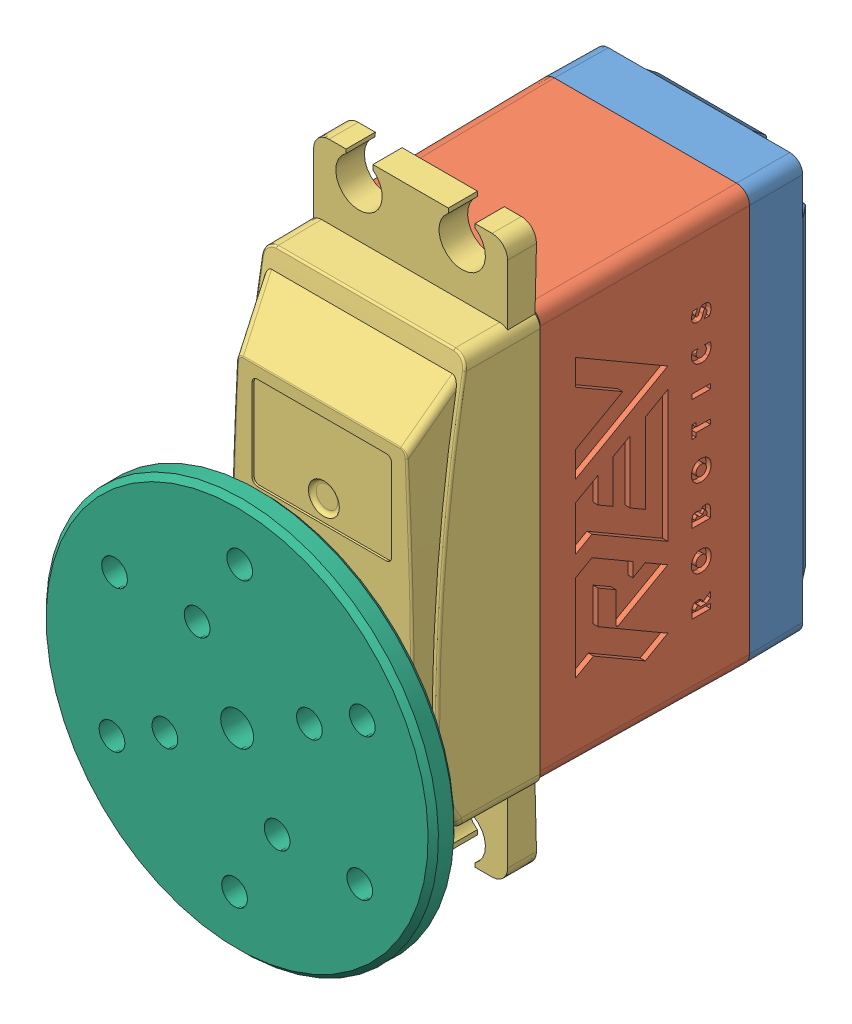
SolidWorks assembly ServoSmartRobotHorn, configuration Default. Lengths in mm.
Overall size (52.15 63.13 46.05).
7 component instances, 6 part files, 2 mates.
Components (placement in the parent):
- PART_ASSEM_ServoSmartRobot-1: PART_ASSEM_ServoSmartRobot [Default] at (95.7961 57.5954 124.6222) size (20.24 54 43.55) (flexible)
  - PART_ServoSmartRobot_A-1: PART_ServoSmartRobot_A [Default] at (-14.7745 1.1024 -40.9494) x (-1 0 0) z (0 0 -1) size (20.15 40.13 8.5)
  - PART_ServoSmartRobot_E-1: PART_ServoSmartRobot_E [Default] at (-14.7741 1.092 -40.9994) x (-1 0 0) z (0 0 -1) size (20.24 40.15 20.1)
  - PART_ServoSmartRobot_C-1: PART_ServoSmartRobot_C [Default] at (-14.7754 0.8648 -41.0494) x (-1 0 0) z (0 0 -1) size (19.8 54 13.28)
  - PART_ServoSmartRobot_B-1: PART_ServoSmartRobot_B [Default] at (-24.5605 -11.4911 -40.9994) x (0.229124 -0.973397 0) z (0 0 -1) size (9 9 4.4)
  - PART_ServoSmartRobot_D-1: PART_ServoSmartRobot_D [Default] at (-14.7754 -9.1878 -10.9994) x (-0.042865 0.999081 0) z (0 0 -1) size (17.2 17.19 14.7)
- PART_ServoSmartRobotHorn_ServoHorn-1: PART_ServoSmartRobotHorn_ServoHorn [Default] at (81.0207 48.4076 129.7228) x (-0.856897 0.515488 0) z (-0.515488 -0.856897 0) size (38 6 38)
Mates (geometry in assembly coordinates):
- Coincident1: coincident anti-aligned: plane of PART_ASSEM_ServoSmartRobot-1/PART_ServoSmartRobot_D-1 through (81.0207 48.4076 127.2228) normal (0 0 1); plane of PART_ServoSmartRobotHorn_ServoHorn-1 through (81.0207 48.4076 127.2228) normal (0 0 -1)
- Concentric1: concentric anti-aligned: cylinder of PART_ASSEM_ServoSmartRobot-1/PART_ServoSmartRobot_D-1 through (81.0207 48.4076 123.7578) axis (0 0 -1) radius 2.5; cylinder of PART_ServoSmartRobotHorn_ServoHorn-1 through (81.0207 48.4076 123.7228) axis (0 0 1) radius 2.7
